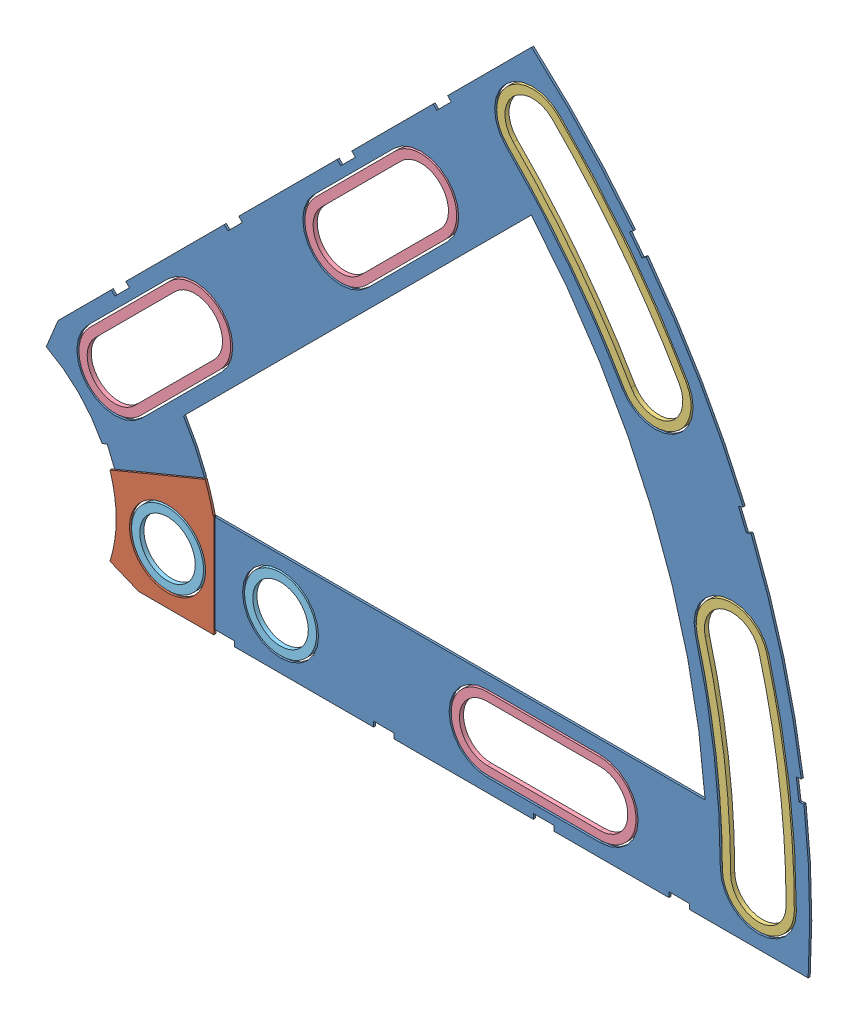
SolidWorks assembly Clover_12_Insul+Pass, configuration Default. Lengths in mm.
Overall size (96.6 82.54 0.51).
9 component instances, 5 part files, 22 mates.
Components (placement in the parent):
- Clover_12_Insul-1: Clover_12_Insul [Default] at (-17.5172 17.5281 69.2543) size (94.37 82.54 0.25)
- Clover_12_Pass-1: Clover_12_Pass [Default] at (-17.5172 17.5281 69.2543) size (12.83 16.1 0.25)
- Clover_Outside_Washer-1: Clover_Outside_Washer [Default] at (-17.5172 17.5281 69.5083) x (0.707107 0.707107 0) z (-0.707107 0.707107 0) size (12.14 0.51 33.54)
- Clover_Outside_Washer-2: Clover_Outside_Washer [Default] at (-17.5172 17.5281 69.5083) x (0.965926 0.258819 0) z (-0.258819 0.965926 0) size (12.14 0.51 33.54)
- Clover_Short_Washer-1: Clover_Short_Washer [Default] at (31.066 66.1113 69.5083) x (0.707107 0.707107 0) z (-0.707107 0.707107 0) size (22.86 0.51 8.89)
- Clover_Short_Washer-2: Clover_Short_Washer [Default] at (3.1374 38.1827 69.5083) x (0.707107 0.707107 0) z (-0.707107 0.707107 0) size (22.86 0.51 8.89)
- Clover_Short_Washer-3: Clover_Short_Washer [Default] at (51.1898 17.5281 69.5083) x (1 0 0) z (0 1 0) size (22.86 0.51 8.89)
- Round_Washer-1: Round_Washer [Default] at (4.7078 17.5281 69.5083) x (1 0 0) z (0 1 0) size (8.89 0.51 8.89)
- Round_Washer-2: Round_Washer [Default] at (18.6778 17.5281 69.5083) x (1 0 0) z (0 1 0) size (8.89 0.51 8.89)
Mates (geometry in assembly coordinates):
- Coincident1: coincident: plane of Clover_12_Insul-1 through (71.1557 23.8781 69.5083) normal (0 1 0); plane of Clover_12_Pass-1 through (71.1557 23.8781 69.5083) normal (0 1 0)
- Concentric1: concentric: cylinder of Clover_12_Insul-1 through (-17.5172 17.5281 69.5083) axis (0 0 -1) radius 28.575; cylinder of Clover_12_Pass-1 through (-17.5172 17.5281 69.5083) axis (0 0 -1) radius 28.575
- Coincident2: coincident: plane of Clover_12_Insul-1 through (-17.5172 17.5281 69.5083) normal (0 0 1); plane of Clover_12_Pass-1 through (-17.5172 17.5281 69.5083) normal (0 0 1)
- Concentric2: concentric: circle of Clover_12_Pass-1; circle of Round_Washer-1
- Coincident3: coincident: plane of Clover_12_Pass-1 through (-17.5172 17.5281 69.5083) normal (0 0 1); plane of Round_Washer-1 through (4.7078 17.5281 69.5083) normal (0 0 1)
- Concentric3: concentric: circle of Clover_12_Insul-1; circle of Round_Washer-2
- Coincident4: coincident: plane of Clover_12_Insul-1 through (-17.5172 17.5281 69.5083) normal (0 0 1); plane of Round_Washer-2 through (18.6778 17.5281 69.5083) normal (0 0 1)
- Concentric4: concentric: circle of Clover_12_Insul-1; circle of Clover_Short_Washer-3
- Concentric5: concentric: circle of Clover_12_Insul-1; circle of Clover_Short_Washer-3
- Coincident5: coincident: plane of Clover_12_Insul-1 through (-17.5172 17.5281 69.5083) normal (0 0 1); plane of Clover_Short_Washer-3 through (44.2048 17.5281 69.5083) normal (0 0 1)
- Concentric6: concentric: circle of Clover_12_Insul-1; circle of Clover_Outside_Washer-2
- Concentric7: concentric: circle of Clover_12_Insul-1; circle of Clover_Outside_Washer-2
- Coincident6: coincident: plane of Clover_12_Insul-1 through (-17.5172 17.5281 69.5083) normal (0 0 1); plane of Clover_Outside_Washer-2 through (28.485 29.8544 69.5083) normal (0 0 1)
- Concentric8: concentric: circle of Clover_12_Insul-1; circle of Clover_Outside_Washer-1
- Concentric9: concentric: circle of Clover_12_Insul-1; circle of Clover_Outside_Washer-1
- Coincident7: coincident: plane of Clover_12_Insul-1 through (-17.5172 17.5281 69.5083) normal (0 0 1); plane of Clover_Outside_Washer-1 through (16.1588 51.2041 69.5083) normal (0 0 1)
- Concentric10: concentric: circle of Clover_12_Insul-1; circle of Clover_Short_Washer-1
- Concentric11: concentric: circle of Clover_12_Insul-1; circle of Clover_Short_Washer-1
- Coincident8: coincident: plane of Clover_12_Insul-1 through (-17.5172 17.5281 69.5083) normal (0 0 1); plane of Clover_Short_Washer-1 through (26.1268 61.1722 69.5083) normal (0 0 1)
- Concentric12: concentric: circle of Clover_12_Insul-1; circle of Clover_Short_Washer-2
- Concentric13: concentric: circle of Clover_12_Insul-1; circle of Clover_Short_Washer-2
- Coincident9: coincident: plane of Clover_12_Insul-1 through (-17.5172 17.5281 69.5083) normal (0 0 1); plane of Clover_Short_Washer-2 through (-1.8018 33.2436 69.5083) normal (0 0 1)
